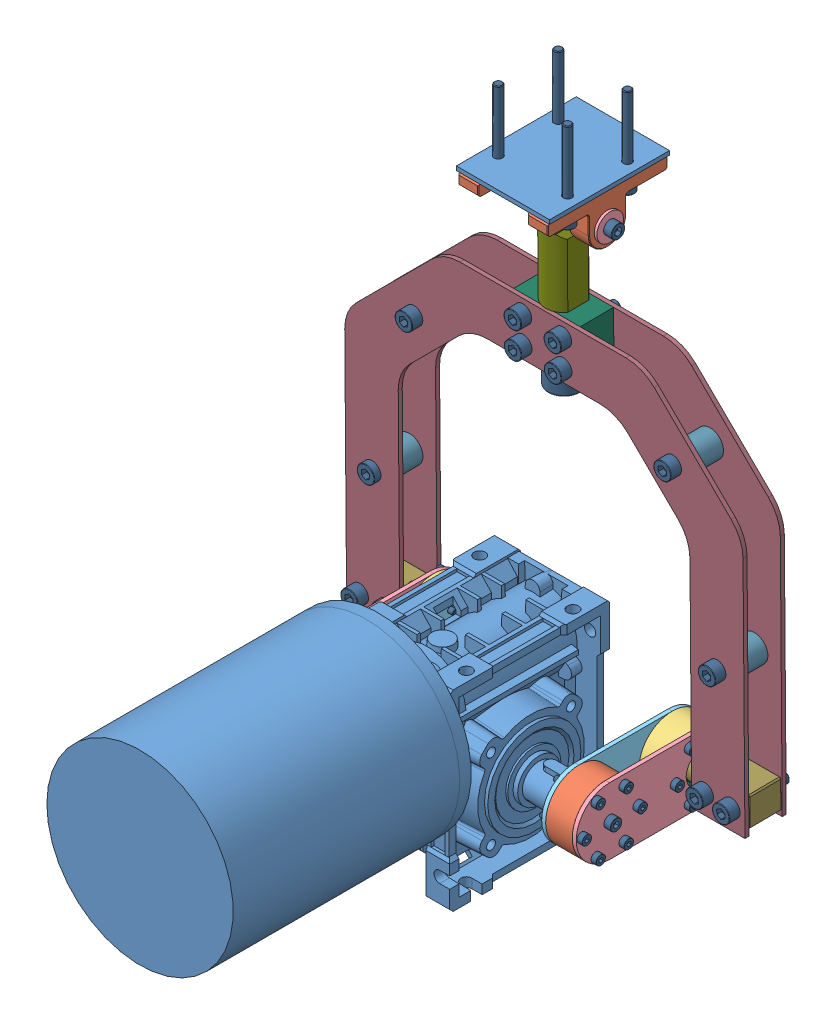
SolidWorks assembly pata con todo, configuration Predeterminado. Lengths in mm.
Overall size (299 452.99 362.47).
126 component instances, 22 part files, 70 mates.
Components (placement in the parent):
- reductor con motor-1: reductor con motor [Predeterminado] at origin size (199 179.97 310)
- manivela con rodamiento derecha-1: manivela con rodamiento derecha [Predeterminado] at (-99.5 -50 -64) x (0 0 -1) z (1 0 0) size (120 50 37)
  - cople flecha-1: cople flecha [Predeterminado] at origin size (50 50 20)
  - cople rodamiento-1: cople rodamiento [Predeterminado] at (70 0 0) size (50 50 20)
  - placa manivela 2-3: placa manivela 2 [Predeterminado] at (0 0 -3) size (120 50 3)
  - placa manivela-2: placa manivela [Predeterminado] at (0 0 20) size (120 50 3)
  - 2202_ETN9-1: 2202_ETN9 [Default] at (70 0 14) x (0 0 -1) z (0.269918 -0.962883 0) size (14 35 35)
    - 2202_ETN9_3-1: 2202_ETN9_3 [Default] x (1 0 0) z (0 -0.587785 0.809017) size (6 6 6)
    - 2202_ETN9_3-2: 2202_ETN9_3 [Default] x (1 0 0) z (0 -0.951057 0.309017) size (6 6 6)
    - 2202_ETN9_3-3: 2202_ETN9_3 [Default] x (1 0 0) z (0 -0.951057 -0.309017) size (6 6 6)
    - 2202_ETN9_3-4: 2202_ETN9_3 [Default] x (1 0 0) z (0 -0.587785 -0.809017) size (6 6 6)
    - 2202_ETN9_3-5: 2202_ETN9_3 [Default] x (1 0 0) z (0 0 -1) size (6 6 6)
    - 2202_ETN9_3-6: 2202_ETN9_3 [Default] x (1 0 0) z (0 0.587785 -0.809017) size (6 6 6)
    - 2202_ETN9_3-7: 2202_ETN9_3 [Default] x (1 0 0) z (0 0.951057 -0.309017) size (6 6 6)
    - 2202_ETN9_3-8: 2202_ETN9_3 [Default] x (1 0 0) z (0 0.951057 0.309017) size (6 6 6)
    - 2202_ETN9_3-9: 2202_ETN9_3 [Default] x (1 0 0) z (0 0.587785 0.809017) size (6 6 6)
    - 2202_ETN9_3-10: 2202_ETN9_3 [Default] at origin size (6 6 6)
    - 2202_ETN9_14-1: 2202_ETN9_14 [Default] x (1 0 0) z (0 -0.587785 0.809017) size (6 6 6)
    - 2202_ETN9_14-2: 2202_ETN9_14 [Default] x (1 0 0) z (0 -0.951057 0.309017) size (6 6 6)
    - 2202_ETN9_14-3: 2202_ETN9_14 [Default] x (1 0 0) z (0 -0.951057 -0.309017) size (6 6 6)
    - 2202_ETN9_14-4: 2202_ETN9_14 [Default] x (1 0 0) z (0 -0.587785 -0.809017) size (6 6 6)
    - 2202_ETN9_14-5: 2202_ETN9_14 [Default] x (1 0 0) z (0 0 -1) size (6 6 6)
    - 2202_ETN9_14-6: 2202_ETN9_14 [Default] x (1 0 0) z (0 0.587785 -0.809017) size (6 6 6)
    - 2202_ETN9_14-7: 2202_ETN9_14 [Default] x (1 0 0) z (0 0.951057 -0.309017) size (6 6 6)
    - 2202_ETN9_14-8: 2202_ETN9_14 [Default] x (1 0 0) z (0 0.951057 0.309017) size (6 6 6)
    - 2202_ETN9_14-9: 2202_ETN9_14 [Default] x (1 0 0) z (0 0.587785 0.809017) size (6 6 6)
    - 2202_ETN9_14-10: 2202_ETN9_14 [Default] at origin size (6 6 6)
    - 2202_ETN9_29-1: 2202_ETN9_29 [Default] at origin size (14 35 35)
    - 2202_ETN9_31-1: 2202_ETN9_31 [Default] at origin size (14 20.86 20.86)
  - socket head cap screw_iso-29: socket head cap screw_iso [ISO 4762 M4 x 30 - 20N] at (-10.5 18.1865 -7) x (0 0 1) z (-1 0 0) size (34 7 7)
  - socket head cap screw_iso-30: socket head cap screw_iso [ISO 4762 M4 x 30 - 20N] at (10.5 18.1865 -4) x (0 0 1) z (-1 0 0) size (34 7 7)
  - socket head cap screw_iso-31: socket head cap screw_iso [ISO 4762 M4 x 30 - 20N] at (21 0 -7) x (0 0 1) z (-1 0 0) size (34 7 7)
  - socket head cap screw_iso-32: socket head cap screw_iso [ISO 4762 M4 x 30 - 20N] at (10.5 -18.1865 -7) x (0 0 1) z (-1 0 0) size (34 7 7)
  - socket head cap screw_iso-33: socket head cap screw_iso [ISO 4762 M4 x 30 - 20N] at (-10.5 -18.1865 -7) x (0 0 1) z (-1 0 0) size (34 7 7)
  - socket head cap screw_iso-34: socket head cap screw_iso [ISO 4762 M4 x 30 - 20N] at (-21 0 -7) x (0 0 1) z (-1 0 0) size (34 7 7)
  - socket head cap screw_iso-35: socket head cap screw_iso [ISO 4762 M4 x 30 - 20N] at (49 0 -7) x (0 0 1) z (-1 0 0) size (34 7 7)
  - socket head cap screw_iso-36: socket head cap screw_iso [ISO 4762 M4 x 30 - 20N] at (59.5 18.1865 -7) x (0 0 1) z (-1 0 0) size (34 7 7)
  - socket head cap screw_iso-37: socket head cap screw_iso [ISO 4762 M4 x 30 - 20N] at (80.5 18.1865 -7) x (0 0 1) z (-1 0 0) size (34 7 7)
  - socket head cap screw_iso-38: socket head cap screw_iso [ISO 4762 M4 x 30 - 20N] at (91 0 -7) x (0 0 1) z (-1 0 0) size (34 7 7)
  - socket head cap screw_iso-39: socket head cap screw_iso [ISO 4762 M4 x 30 - 20N] at (80.5 -18.1865 -7) x (0 0 1) z (-1 0 0) size (34 7 7)
  - socket head cap screw_iso-40: socket head cap screw_iso [ISO 4762 M4 x 30 - 20N] at (59.5 -18.1865 -7) x (0 0 1) z (-1 0 0) size (34 7 7)
  - anillo manivela-1: anillo manivela [Predeterminado] at (70 0 14) size (35 35 6)
- manivela con rodamiento-2: manivela con rodamiento [Predeterminado] at (79.5 -50 -64) x (0 0 -1) z (1 0 0) size (120 50 208.83)
  - cople flecha-1: cople flecha [Predeterminado] at origin size (50 50 20)
  - cople rodamiento-1: cople rodamiento [Predeterminado] at (70 0 0) size (50 50 20)
  - placa manivela-1: placa manivela [Predeterminado] at (0 0 -3) size (120 50 3)
  - placa manivela 2-2: placa manivela 2 [Predeterminado] at (0 0 20) size (120 50 3)
  - 2202_ETN9-1: 2202_ETN9 [Default] at (70 0 20) x (0 0 -1) z (1 0 0) size (14 35 35)
    - 2202_ETN9_3-1: 2202_ETN9_3 [Default] x (1 0 0) z (0 -0.587785 0.809017) size (6 6 6)
    - 2202_ETN9_3-2: 2202_ETN9_3 [Default] x (1 0 0) z (0 -0.951057 0.309017) size (6 6 6)
    - 2202_ETN9_3-3: 2202_ETN9_3 [Default] x (1 0 0) z (0 -0.951057 -0.309017) size (6 6 6)
    - 2202_ETN9_3-4: 2202_ETN9_3 [Default] x (1 0 0) z (0 -0.587785 -0.809017) size (6 6 6)
    - 2202_ETN9_3-5: 2202_ETN9_3 [Default] x (1 0 0) z (0 0 -1) size (6 6 6)
    - 2202_ETN9_3-6: 2202_ETN9_3 [Default] x (1 0 0) z (0 0.587785 -0.809017) size (6 6 6)
    - 2202_ETN9_3-7: 2202_ETN9_3 [Default] x (1 0 0) z (0 0.951057 -0.309017) size (6 6 6)
    - 2202_ETN9_3-8: 2202_ETN9_3 [Default] x (1 0 0) z (0 0.951057 0.309017) size (6 6 6)
    - 2202_ETN9_3-9: 2202_ETN9_3 [Default] x (1 0 0) z (0 0.587785 0.809017) size (6 6 6)
    - 2202_ETN9_3-10: 2202_ETN9_3 [Default] at origin size (6 6 6)
    - 2202_ETN9_14-1: 2202_ETN9_14 [Default] x (1 0 0) z (0 -0.587785 0.809017) size (6 6 6)
    - 2202_ETN9_14-2: 2202_ETN9_14 [Default] x (1 0 0) z (0 -0.951057 0.309017) size (6 6 6)
    - 2202_ETN9_14-3: 2202_ETN9_14 [Default] x (1 0 0) z (0 -0.951057 -0.309017) size (6 6 6)
    - 2202_ETN9_14-4: 2202_ETN9_14 [Default] x (1 0 0) z (0 -0.587785 -0.809017) size (6 6 6)
    - 2202_ETN9_14-5: 2202_ETN9_14 [Default] x (1 0 0) z (0 0 -1) size (6 6 6)
    - 2202_ETN9_14-6: 2202_ETN9_14 [Default] x (1 0 0) z (0 0.587785 -0.809017) size (6 6 6)
    - 2202_ETN9_14-7: 2202_ETN9_14 [Default] x (1 0 0) z (0 0.951057 -0.309017) size (6 6 6)
    - 2202_ETN9_14-8: 2202_ETN9_14 [Default] x (1 0 0) z (0 0.951057 0.309017) size (6 6 6)
    - 2202_ETN9_14-9: 2202_ETN9_14 [Default] x (1 0 0) z (0 0.587785 0.809017) size (6 6 6)
    - 2202_ETN9_14-10: 2202_ETN9_14 [Default] at origin size (6 6 6)
    - 2202_ETN9_29-1: 2202_ETN9_29 [Default] at origin size (14 35 35)
    - 2202_ETN9_31-1: 2202_ETN9_31 [Default] at origin size (14 20.86 20.86)
  - socket head cap screw_iso-16: socket head cap screw_iso [ISO 4762 M4 x 30 - 20N] at (-10.5 18.1865 27) x (0 0 -1) z (1 0 0) size (34 7 7)
  - socket head cap screw_iso-17: socket head cap screw_iso [ISO 4762 M4 x 30 - 20N] at (10.5 18.1865 27) x (0 0 -1) z (1 0 0) size (34 7 7)
  - socket head cap screw_iso-18: socket head cap screw_iso [ISO 4762 M4 x 30 - 20N] at (21 0 27) x (0 0 -1) z (1 0 0) size (34 7 7)
  - socket head cap screw_iso-19: socket head cap screw_iso [ISO 4762 M4 x 30 - 20N] at (10.5 -18.1865 27) x (0 0 -1) z (1 0 0) size (34 7 7)
  - socket head cap screw_iso-20: socket head cap screw_iso [ISO 4762 M4 x 30 - 20N] at (-10.5 -18.1865 27) x (0 0 -1) z (1 0 0) size (34 7 7)
  - socket head cap screw_iso-21: socket head cap screw_iso [ISO 4762 M4 x 30 - 20N] at (-21 0 27) x (0 0 -1) z (1 0 0) size (34 7 7)
  - socket head cap screw_iso-22: socket head cap screw_iso [ISO 4762 M4 x 30 - 20N] at (59.5 18.1865 27) x (0 0 -1) z (1 0 0) size (34 7 7)
  - socket head cap screw_iso-23: socket head cap screw_iso [ISO 4762 M4 x 30 - 20N] at (49 0 27) x (0 0 -1) z (1 0 0) size (34 7 7)
  - socket head cap screw_iso-24: socket head cap screw_iso [ISO 4762 M4 x 30 - 20N] at (59.5 -18.1865 27) x (0 0 -1) z (1 0 0) size (34 7 7)
  - socket head cap screw_iso-25: socket head cap screw_iso [ISO 4762 M4 x 30 - 20N] at (80.5 -18.1865 27) x (0 0 -1) z (1 0 0) size (34 7 7)
  - socket head cap screw_iso-26: socket head cap screw_iso [ISO 4762 M4 x 30 - 20N] at (91 0 27) x (0 0 -1) z (1 0 0) size (34 7 7)
  - socket head cap screw_iso-27: socket head cap screw_iso [ISO 4762 M4 x 30 - 20N] at (80.5 18.1865 27) x (0 0 -1) z (1 0 0) size (34 7 7)
  - anillo manivela-1: anillo manivela [Predeterminado] at (70 0 0) size (35 35 6)
- socket head cap screw_iso-4: socket head cap screw_iso [ISO 4762 M5 x 10 - 10N] at (107.5 -50 -64) x (-1 0 0) z (0 0.924225 0.381849) size (15 8.5 8.5)
- socket head cap screw_iso-5: socket head cap screw_iso [ISO 4762 M5 x 10 - 10N] at (-107.5 -50 -64) size (15 8.5 8.5)
- pin de manivela-2: pin de manivela [Predeterminado] at (-74.5 -50 -134) x (1 0 0) z (0 0.007936 -0.999969) size (75 22 25)
- pin de manivela-3: pin de manivela [Predeterminado] at (74.5 -50 -134) x (-1 0 0) z (0 0.007936 -0.999969) size (75 22 25)
- arco ensamble-2: arco ensamble [Predeterminado] at (0 -64.8765 -149.6186) x (1 0 0) z (0 -0.007936 0.999969) size (299 270 31)
  - arco-1: arco [Predeterminado] at origin size (299 270 3)
  - arco-2: arco [Predeterminado] at (0 0 28) size (299 270 3)
  - virlo-1: virlo [Predeterminado] at (-129.5 100.125 3) x (0.157699 0.987487 0) z (0 0 1) size (20 20 25)
  - virlo-2: virlo [Predeterminado] at (-97.125 217.625 3) size (20 20 25)
  - virlo-3: virlo [Predeterminado] at (97.125 217.625 3) size (20 20 25)
  - virlo-4: virlo [Predeterminado] at (129.5 100.125 3) size (20 20 25)
  - bloque-1: bloque [Predeterminado] at (0 250 15.5) size (50 40 25)
- socket head cap screw_iso-9: socket head cap screw_iso [ISO 4762 M8 x 40 - 28N] at (139.5 -50.1865 -110.5007) x (0 0.007936 -0.999969) z (0.999973 0.00736 0.000058) size (48 13 13)
- socket head cap screw_iso-10: socket head cap screw_iso [ISO 4762 M8 x 40 - 28N] at (119.5 -50.1865 -110.5007) x (0 0.007936 -0.999969) z (0.999973 0.00736 0.000058) size (48 13 13)
- socket head cap screw_iso-11: socket head cap screw_iso [ISO 4762 M8 x 40 - 28N] at (129.5 34.9358 -109.8252) x (0 0.007936 -0.999969) z (0.999973 0.00736 0.000058) size (48 13 13)
- socket head cap screw_iso-12: socket head cap screw_iso [ISO 4762 M8 x 40 - 28N] at (97.125 152.4321 -108.8927) x (0 0.007936 -0.999969) z (0.999973 0.00736 0.000058) size (48 13 13)
- socket head cap screw_iso-13: socket head cap screw_iso [ISO 4762 M8 x 40 - 28N] at (-97.125 152.4321 -108.8927) x (0 0.007936 -0.999969) z (0.999973 0.00736 0.000058) size (48 13 13)
- socket head cap screw_iso-14: socket head cap screw_iso [ISO 4762 M8 x 40 - 28N] at (-129.5 34.9596 -112.8251) x (0 0.007936 -0.999969) z (0.999973 0.00736 0.000058) size (48 13 13)
- socket head cap screw_iso-15: socket head cap screw_iso [ISO 4762 M8 x 40 - 28N] at (-139.5 -50.1865 -110.5007) x (0 0.007936 -0.999969) z (0.999973 0.00736 0.000058) size (48 13 13)
- socket head cap screw_iso-16: socket head cap screw_iso [ISO 4762 M8 x 40 - 28N] at (-119.5 -50.1627 -113.5006) x (0 0.007936 -0.999969) z (0.999973 0.00736 0.000058) size (48 13 13)
- socket head cap screw_iso-17: socket head cap screw_iso [ISO 4762 M8 x 40 - 28N] at (-15 194.8058 -108.5564) x (0 0.007936 -0.999969) z (0.999973 0.00736 0.000058) size (48 13 13)
- socket head cap screw_iso-18: socket head cap screw_iso [ISO 4762 M8 x 40 - 28N] at (-15 174.8064 -108.7151) x (0 0.007936 -0.999969) z (0.999973 0.00736 0.000058) size (48 13 13)
- socket head cap screw_iso-19: socket head cap screw_iso [ISO 4762 M8 x 40 - 28N] at (15 194.8058 -108.5564) x (0 0.007936 -0.999969) z (0.999973 0.00736 0.000058) size (48 13 13)
- socket head cap screw_iso-20: socket head cap screw_iso [ISO 4762 M8 x 40 - 28N] at (15 174.8064 -108.7151) x (0 0.007936 -0.999969) z (0.999973 0.00736 0.000058) size (48 13 13)
- Rotula de esfera-1: Rotula de esfera [M16] at (0 204.992 -131.9763) x (0 0.007936 -0.999969) z (1 0 0) size (38 83 22)
  - rotula-1: rotula [M16] at origin size (38 83 22)
  - esfera-1: esfera [M16] at (0 64 0) size (30 30 21)
- socket head cap screw_iso-22: socket head cap screw_iso [ISO 4762 M16 x 60 - 60N] at (0 148.9937 -132.4207) x (0 0.999969 0.007936) z (-0.00736 -0.007936 0.999941) size (76 24 24)
- pin superior-1: pin superior [Predeterminado] at (0 268.99 -131.4684) size (67 16 16)
- soperte superior-1: soperte superior [Predeterminado] at (0 292.99 -131.4684) size (70 41 90)
  - placa superior-1: placa superior [Predeterminado] at origin size (70 3 90)
  - soporte superior-1: soporte superior [Predeterminado] at (-26 -24 0) x (0 0 1) z (-1 0 0) size (90 38 15)
  - soporte superior-2: soporte superior [Predeterminado] at (26 -24 0) x (0 0 1) z (-1 0 0) size (90 38 15)
- virlo superior-1: virlo superior [Predeterminado] at (18.5 268.99 -131.4684) x (0 -0.000576 1) z (-1 0 0) size (22 22 8)
- virlo superior-2: virlo superior [Predeterminado] at (-10.5 268.99 -131.4684) x (0 0 1) z (-1 0 0) size (22 22 8)
- socket head cap screw_iso-24: socket head cap screw_iso [ISO 4762 M6 x 60 - 60N] at (-26 276.99 -108.9684) x (0 1 0) z (0 0 1) size (66 10 10)
- socket head cap screw_iso-25: socket head cap screw_iso [ISO 4762 M6 x 60 - 60N] at (26 276.99 -108.9684) x (0 1 0) z (0 0 1) size (66 10 10)
- socket head cap screw_iso-26: socket head cap screw_iso [ISO 4762 M6 x 60 - 60N] at (-26 276.99 -153.9684) x (0 1 0) z (0 0 1) size (66 10 10)
- socket head cap screw_iso-27: socket head cap screw_iso [ISO 4762 M6 x 60 - 60N] at (26 276.99 -153.9684) x (0 1 0) z (0 0 1) size (66 10 10)
- plain washer 10669 type nl_iso-2: plain washer 10669 type nl_iso [ISO 10669-8.8-N] at (33.5 268.99 -131.4684) size (2 20 20)
- plain washer 10669 type nl_iso-3: plain washer 10669 type nl_iso [ISO 10669-8.8-N] at (-33.5 268.99 -131.4684) x (-1 0 0) z (0 0.924225 0.381849) size (2 20 20)
- socket head cap screw_iso-29: socket head cap screw_iso [ISO 4762 M6 x 16 - 16N] at (-41.5 268.99 -131.4684) size (22 10 10)
- socket head cap screw_iso-30: socket head cap screw_iso [ISO 4762 M6 x 16 - 16N] at (41.5 268.99 -131.4684) x (-1 0 0) z (0 0.924225 0.381849) size (22 10 10)
Mates (geometry in assembly coordinates):
- Concéntrica1: concentric anti-aligned: cylinder of reductor con motor-1 through (-49.5 -50 -64) axis (-1 0 0) radius 12.5; cylinder of manivela con rodamiento derecha-1/cople flecha-1 through (-99.5 -50 -64) axis (1 0 0) radius 13
- Paralelo1: parallel anti-aligned: plane of reductor con motor-1 through (-54.5 -34.5 -68) normal (0 1 0); plane of manivela con rodamiento derecha-1/cople flecha-1 through (-99.5 -33.7 -68) normal (0 -1 0)
- Coincidente2: coincident anti-aligned: plane of reductor con motor-1 through (-99.5 -50 -64) normal (-1 0 0); plane of manivela con rodamiento derecha-1/placa manivela 2-3 through (-99.5 -50 -64) normal (1 0 0)
- Concéntrica3: concentric aligned: cylinder of reductor con motor-1 through (49.5 -50 -64) axis (1 0 0) radius 12.5; cylinder of manivela con rodamiento-2/cople flecha-1 through (79.5 -50 -64) axis (1 0 0) radius 13
- Paralelo2: parallel anti-aligned: plane of reductor con motor-1 through (54.5 -34.5 -68) normal (0 1 0); plane of manivela con rodamiento-2/cople flecha-1 through (79.5 -33.7 -68) normal (0 -1 0)
- Concéntrica4: concentric aligned: cylinder of manivela con rodamiento-2/placa manivela 2-2 through (102.5 -50 -64) axis (1 0 0) radius 2.65; cylinder of socket head cap screw_iso-4 through (139.25 -50 -64) axis (1 0 0) radius 4.25
- Coincidente5: coincident anti-aligned: plane of manivela con rodamiento-2/placa manivela 2-2 through (102.5 -50 -64) normal (1 0 0); plane of socket head cap screw_iso-4 through (102.5 -51.6229 -60.072) normal (-1 0 0)
- Concéntrica5: concentric anti-aligned: cylinder of manivela con rodamiento derecha-1/placa manivela 2-3 through (-99.5 -50 -64) axis (1 0 0) radius 2.65; cylinder of socket head cap screw_iso-5 through (-139.25 -50 -64) axis (-1 0 0) radius 4.25
- Coincidente6: coincident anti-aligned: plane of manivela con rodamiento derecha-1/placa manivela 2-3 through (-102.5 -50 -64) normal (-1 0 0); plane of socket head cap screw_iso-5 through (-102.5 -45.75 -64) normal (1 0 0)
- Concéntrica7: concentric aligned: cylinder of manivela con rodamiento derecha-1/2202_ETN9-1/2202_ETN9_31-1 through (-135.5 -50 -134) axis (-1 0 0) radius 7.5; cylinder of pin de manivela-2 through (-149.5 -50 -134) axis (-1 0 0) radius 7.5
- Concéntrica8: concentric anti-aligned: cylinder of manivela con rodamiento-2/2202_ETN9-1/2202_ETN9_31-1 through (49.5 -50 -134) axis (-1 0 0) radius 7.5; cylinder of pin de manivela-3 through (149.5 -50 -134) axis (1 0 0) radius 7.5
- Coincidente8: coincident anti-aligned: plane of reductor con motor-1 through (99.5 -50 -64) normal (1 0 0); plane of manivela con rodamiento-2/placa manivela 2-2 through (99.5 -50 -64) normal (-1 0 0)
- Coincidente9: coincident anti-aligned: plane of manivela con rodamiento-2/2202_ETN9-1/2202_ETN9_31-1 through (99.5 -39.77 -134) normal (1 0 0); plane of pin de manivela-3 through (99.5 -42.5002 -133.9405) normal (-1 0 0)
- Coincidente12: coincident anti-aligned: plane of manivela con rodamiento derecha-1/2202_ETN9-1/2202_ETN9_31-1 through (-99.5 -47.8137 -141.7994) normal (-1 0 0); plane of pin de manivela-2 through (-99.5 -57.4998 -134.0595) normal (1 0 0)
- Concéntrica9: concentric anti-aligned: cylinder of pin de manivela-2 through (-139.5 -49.9008 -146.4996) axis (0 0.007936 -0.999969) radius 4.2; cylinder of arco ensamble-2/arco-2 through (-139.5 -50.123 -118.5005) axis (0 -0.007936 0.999969) radius 4.2
- Coincidente13: coincident anti-aligned: plane of pin de manivela-2 through (-149.5 -38.9011 -146.4123) normal (0 0.007936 -0.999969); plane of arco ensamble-2/arco-1 through (119.5 117.9175 -145.1677) normal (0 -0.007936 0.999969)
- Concéntrica10: concentric anti-aligned: cylinder of pin de manivela-3 through (119.5 -49.9008 -146.4996) axis (0 0.007936 -0.999969) radius 4.2; cylinder of arco ensamble-2/arco-2 through (119.5 -50.123 -118.5005) axis (0 -0.007936 0.999969) radius 4.2
- Concéntrica12: concentric aligned: cylinder of arco ensamble-2/arco-2 through (139.5 -50.123 -118.5005) axis (0 -0.007936 0.999969) radius 4.2; cylinder of socket head cap screw_iso-9 through (139.5 -50.4385 -78.7517) axis (0 -0.007936 0.999969) radius 6.5
- Coincidente15: coincident anti-aligned: plane of arco ensamble-2/arco-2 through (119.5 117.6953 -117.1686) normal (0 -0.007936 0.999969); plane of socket head cap screw_iso-9 through (139.4522 -43.6234 -118.4489) normal (0 0.007936 -0.999969)
- Concéntrica13: concentric aligned: cylinder of arco ensamble-2/arco-2 through (119.5 -50.123 -118.5005) axis (0 -0.007936 0.999969) radius 4.2; cylinder of socket head cap screw_iso-10 through (119.5 -50.4385 -78.7517) axis (0 -0.007936 0.999969) radius 6.5
- Coincidente16: coincident anti-aligned: plane of arco ensamble-2/arco-2 through (119.5 117.6953 -117.1686) normal (0 -0.007936 0.999969); plane of socket head cap screw_iso-10 through (119.4522 -43.6234 -118.4489) normal (0 0.007936 -0.999969)
- Concéntrica14: concentric aligned: cylinder of arco ensamble-2/arco-2 through (129.5 34.9993 -117.8249) axis (0 -0.007936 0.999969) radius 4.2; cylinder of socket head cap screw_iso-11 through (129.5 34.6838 -78.0762) axis (0 -0.007936 0.999969) radius 6.5
- Coincidente17: coincident anti-aligned: plane of arco ensamble-2/arco-2 through (119.5 117.6953 -117.1686) normal (0 -0.007936 0.999969); plane of socket head cap screw_iso-11 through (129.4522 41.4989 -117.7733) normal (0 0.007936 -0.999969)
- Concéntrica15: concentric aligned: cylinder of arco ensamble-2/arco-2 through (97.125 152.4956 -116.8924) axis (0 -0.007936 0.999969) radius 4.2; cylinder of socket head cap screw_iso-12 through (97.125 152.1801 -77.1437) axis (0 -0.007936 0.999969) radius 6.5
- Coincidente18: coincident anti-aligned: plane of arco ensamble-2/arco-2 through (119.5 117.6953 -117.1686) normal (0 -0.007936 0.999969); plane of socket head cap screw_iso-12 through (97.0772 158.9952 -116.8408) normal (0 0.007936 -0.999969)
- Concéntrica16: concentric aligned: cylinder of arco ensamble-2/arco-2 through (-97.125 152.4956 -116.8924) axis (0 -0.007936 0.999969) radius 4.2; cylinder of socket head cap screw_iso-13 through (-97.125 152.1801 -77.1437) axis (0 -0.007936 0.999969) radius 6.5
- Coincidente19: coincident anti-aligned: plane of arco ensamble-2/arco-2 through (119.5 117.6953 -117.1686) normal (0 -0.007936 0.999969); plane of socket head cap screw_iso-13 through (-97.1728 158.9952 -116.8408) normal (0 0.007936 -0.999969)
- Concéntrica171: concentric aligned: cylinder of arco ensamble-2/virlo-1 through (-129.5 35.0231 -120.8248) axis (0 -0.007936 0.999969) radius 4.2; cylinder of socket head cap screw_iso-14 through (-129.5 34.7077 -81.0761) axis (0 -0.007936 0.999969) radius 6.5
- Coincidente201: coincident anti-aligned: plane of arco ensamble-2/virlo-1 through (-129.5 35.0231 -120.8248) normal (0 -0.007936 0.999969); plane of socket head cap screw_iso-14 through (-129.5478 41.5227 -120.7732) normal (0 0.007936 -0.999969)
- Concéntrica18: concentric aligned: cylinder of arco ensamble-2/arco-2 through (-139.5 -50.123 -118.5005) axis (0 -0.007936 0.999969) radius 4.2; cylinder of socket head cap screw_iso-15 through (-139.5 -50.4385 -78.7517) axis (0 -0.007936 0.999969) radius 6.5
- Coincidente21: coincident anti-aligned: plane of arco ensamble-2/arco-2 through (119.5 117.6953 -117.1686) normal (0 -0.007936 0.999969); plane of socket head cap screw_iso-15 through (-139.5478 -43.6234 -118.4489) normal (0 0.007936 -0.999969)
- Concéntrica19: concentric anti-aligned: cylinder of pin de manivela-2 through (-119.5 -49.9008 -146.4996) axis (0 0.007936 -0.999969) radius 4.2; cylinder of socket head cap screw_iso-16 through (-119.5 -50.4147 -81.7516) axis (0 -0.007936 0.999969) radius 6.5
- Coincidente22: coincident anti-aligned: plane of pin de manivela-2 through (-149.5 -39.0995 -121.4131) normal (0 -0.007936 0.999969); plane of socket head cap screw_iso-16 through (-119.5478 -43.5996 -121.4488) normal (0 0.007936 -0.999969)
- Concéntrica20: concentric aligned: cylinder of arco ensamble-2/arco-2 through (-15 194.8693 -116.5561) axis (0 -0.007936 0.999969) radius 4.2; cylinder of socket head cap screw_iso-17 through (-15 194.5538 -76.8074) axis (0 -0.007936 0.999969) radius 6.5
- Coincidente23: coincident anti-aligned: plane of arco ensamble-2/arco-2 through (119.5 117.6953 -117.1686) normal (0 -0.007936 0.999969); plane of socket head cap screw_iso-17 through (-15.0478 201.3689 -116.5045) normal (0 0.007936 -0.999969)
- Concéntrica21: concentric aligned: cylinder of arco ensamble-2/arco-2 through (-15 174.8699 -116.7149) axis (0 -0.007936 0.999969) radius 4.2; cylinder of socket head cap screw_iso-18 through (-15 174.5544 -76.9661) axis (0 -0.007936 0.999969) radius 6.5
- Coincidente24: coincident anti-aligned: plane of arco ensamble-2/arco-2 through (119.5 117.6953 -117.1686) normal (0 -0.007936 0.999969); plane of socket head cap screw_iso-18 through (-15.0478 181.3695 -116.6633) normal (0 0.007936 -0.999969)
- Concéntrica22: concentric aligned: cylinder of arco ensamble-2/arco-2 through (15 194.8693 -116.5561) axis (0 -0.007936 0.999969) radius 4.2; cylinder of socket head cap screw_iso-19 through (15 194.5538 -76.8074) axis (0 -0.007936 0.999969) radius 6.5
- Coincidente25: coincident anti-aligned: plane of arco ensamble-2/arco-2 through (119.5 117.6953 -117.1686) normal (0 -0.007936 0.999969); plane of socket head cap screw_iso-19 through (14.9522 201.3689 -116.5045) normal (0 0.007936 -0.999969)
- Concéntrica23: concentric aligned: cylinder of arco ensamble-2/arco-2 through (15 174.8699 -116.7149) axis (0 -0.007936 0.999969) radius 4.2; cylinder of socket head cap screw_iso-20 through (15 174.5544 -76.9661) axis (0 -0.007936 0.999969) radius 6.5
- Coincidente26: coincident anti-aligned: plane of arco ensamble-2/arco-2 through (119.5 117.6953 -117.1686) normal (0 -0.007936 0.999969); plane of socket head cap screw_iso-20 through (14.9522 181.3695 -116.6633) normal (0 0.007936 -0.999969)
- Coincidente27: coincident anti-aligned: plane of arco ensamble-2/bloque-1 through (-25 204.8928 -119.4767) normal (0 0.999969 0.007936); plane of Rotula de esfera-1/rotula-1 through (0 204.992 -131.9763) normal (0 -0.999969 -0.007936)
- Concéntrica24: concentric anti-aligned: cylinder of arco ensamble-2/bloque-1 through (0 204.992 -131.9763) axis (0 0.999969 0.007936) radius 8.5; cylinder of Rotula de esfera-1/rotula-1 through (0 204.992 -131.9763) axis (0 -0.999969 -0.007936) radius 8.75
- Paralelo3: parallel anti-aligned: plane of arco ensamble-2/bloque-1 through (-25 164.894 -119.7941) normal (-1 0 0); plane of Rotula de esfera-1/rotula-1 through (11 204.8412 -112.9769) normal (1 0 0)
- Concéntrica25: concentric anti-aligned: cylinder of arco ensamble-2/bloque-1 through (0 204.992 -131.9763) axis (0 0.999969 0.007936) radius 8.5; cylinder of socket head cap screw_iso-22 through (0 117.2447 -132.6727) axis (0 -0.999969 -0.007936) radius 12
- Coincidente29: coincident anti-aligned: plane of arco ensamble-2/bloque-1 through (-25 164.894 -119.7941) normal (0 -0.999969 -0.007936); plane of socket head cap screw_iso-22 through (-11.9997 164.9939 -132.382) normal (0 0.999969 0.007936)
- Concéntrica26: concentric anti-aligned: cylinder of Rotula de esfera-1/esfera-1 through (-15 268.99 -131.4684) axis (1 0 0) radius 8; cylinder of pin superior-1 through (33.5 268.99 -131.4684) axis (-1 0 0) radius 8
- Concéntrica27: concentric anti-aligned: cylinder of pin superior-1 through (33.5 268.99 -131.4684) axis (-1 0 0) radius 8; cylinder of soperte superior-1/soporte superior-2 through (18.5 268.99 -131.4684) axis (1 0 0) radius 8
- Coincidente30: coincident aligned: plane of pin superior-1 through (33.5 268.99 -131.4684) normal (1 0 0); plane of soperte superior-1/soporte superior-2 through (33.5 268.99 -131.4684) normal (1 0 0)
- Concéntrica28: concentric anti-aligned: cylinder of pin superior-1 through (33.5 268.99 -131.4684) axis (-1 0 0) radius 8; cylinder of virlo superior-2 through (-18.5 268.99 -131.4684) axis (1 0 0) radius 8
- Coincidente31: coincident anti-aligned: plane of soperte superior-1/soporte superior-1 through (-18.5 268.99 -131.4684) normal (1 0 0); plane of virlo superior-2 through (-18.5 268.99 -131.4684) normal (-1 0 0)
- Concéntrica29: concentric anti-aligned: cylinder of pin superior-1 through (33.5 268.99 -131.4684) axis (-1 0 0) radius 8; cylinder of virlo superior-1 through (10.5 268.99 -131.4684) axis (1 0 0) radius 8
- Coincidente32: coincident anti-aligned: plane of soperte superior-1/soporte superior-2 through (18.5 268.99 -131.4684) normal (-1 0 0); plane of virlo superior-1 through (18.5 268.99 -131.4684) normal (1 0 0)
- Coincidente33: coincident anti-aligned: plane of Rotula de esfera-1/esfera-1 through (10.5 258.1591 -116.5539) normal (1 0 0); plane of virlo superior-1 through (10.5 268.99 -131.4684) normal (-1 0 0)
- Concéntrica30: concentric aligned: cylinder of soperte superior-1/soporte superior-1 through (-26 282.99 -108.9684) axis (0 -1 0) radius 3.2; cylinder of socket head cap screw_iso-24 through (-26 245.24 -108.9684) axis (0 -1 0) radius 5
- Coincidente34: coincident anti-aligned: plane of soperte superior-1/soporte superior-1 through (-33.5 282.99 -131.4684) normal (0 -1 0); plane of socket head cap screw_iso-24 through (-31 282.99 -108.9684) normal (0 1 0)
- Concéntrica31: concentric aligned: cylinder of soperte superior-1/soporte superior-2 through (26 282.99 -108.9684) axis (0 -1 0) radius 3.2; cylinder of socket head cap screw_iso-25 through (26 245.24 -108.9684) axis (0 -1 0) radius 5
- Coincidente35: coincident anti-aligned: plane of soperte superior-1/soporte superior-2 through (18.5 282.99 -131.4684) normal (0 -1 0); plane of socket head cap screw_iso-25 through (21 282.99 -108.9684) normal (0 1 0)
- Concéntrica32: concentric aligned: cylinder of soperte superior-1/soporte superior-1 through (-26 282.99 -153.9684) axis (0 -1 0) radius 3.2; cylinder of socket head cap screw_iso-26 through (-26 245.24 -153.9684) axis (0 -1 0) radius 5
- Coincidente36: coincident anti-aligned: plane of soperte superior-1/soporte superior-1 through (-33.5 282.99 -131.4684) normal (0 -1 0); plane of socket head cap screw_iso-26 through (-31 282.99 -153.9684) normal (0 1 0)
- Concéntrica33: concentric aligned: cylinder of soperte superior-1/soporte superior-2 through (26 282.99 -153.9684) axis (0 -1 0) radius 3.2; cylinder of socket head cap screw_iso-27 through (26 245.24 -153.9684) axis (0 -1 0) radius 5
- Coincidente37: coincident anti-aligned: plane of soperte superior-1/soporte superior-2 through (18.5 282.99 -131.4684) normal (0 -1 0); plane of socket head cap screw_iso-27 through (21 282.99 -153.9684) normal (0 1 0)
- Concéntrica172: concentric anti-aligned: cylinder of pin superior-1 through (33.5 268.99 -131.4684) axis (1 0 0) radius 3.2; cylinder of plain washer 10669 type nl_iso-2 through (35.5 268.99 -131.4684) axis (-1 0 0) radius 4.4
- Coincidente202: coincident anti-aligned: plane of pin superior-1 through (33.5 268.99 -131.4684) normal (1 0 0); plane of plain washer 10669 type nl_iso-2 through (33.5 268.99 -131.4684) normal (-1 0 0)
- Concéntrica173: concentric anti-aligned: cylinder of pin superior-1 through (-33.5 268.99 -131.4684) axis (-1 0 0) radius 3.2; cylinder of plain washer 10669 type nl_iso-3 through (-35.5 268.99 -131.4684) axis (1 0 0) radius 4.4
- Coincidente203: coincident anti-aligned: plane of pin superior-1 through (-33.5 268.99 -131.4684) normal (-1 0 0); plane of plain washer 10669 type nl_iso-3 through (-33.5 268.99 -131.4684) normal (1 0 0)
- Concéntrica174: concentric aligned: cylinder of pin superior-1 through (-33.5 268.99 -131.4684) axis (-1 0 0) radius 3.2; cylinder of socket head cap screw_iso-29 through (-73.25 268.99 -131.4684) axis (-1 0 0) radius 5
- Coincidente204: coincident anti-aligned: plane of plain washer 10669 type nl_iso-3 through (-35.5 268.99 -131.4684) normal (-1 0 0); plane of socket head cap screw_iso-29 through (-35.5 273.99 -131.4684) normal (1 0 0)
- Concéntrica175: concentric aligned: cylinder of pin superior-1 through (33.5 268.99 -131.4684) axis (1 0 0) radius 3.2; cylinder of socket head cap screw_iso-30 through (73.25 268.99 -131.4684) axis (1 0 0) radius 5
- Coincidente205: coincident anti-aligned: plane of plain washer 10669 type nl_iso-2 through (35.5 268.99 -131.4684) normal (1 0 0); plane of socket head cap screw_iso-30 through (35.5 267.0807 -126.8472) normal (-1 0 0)
